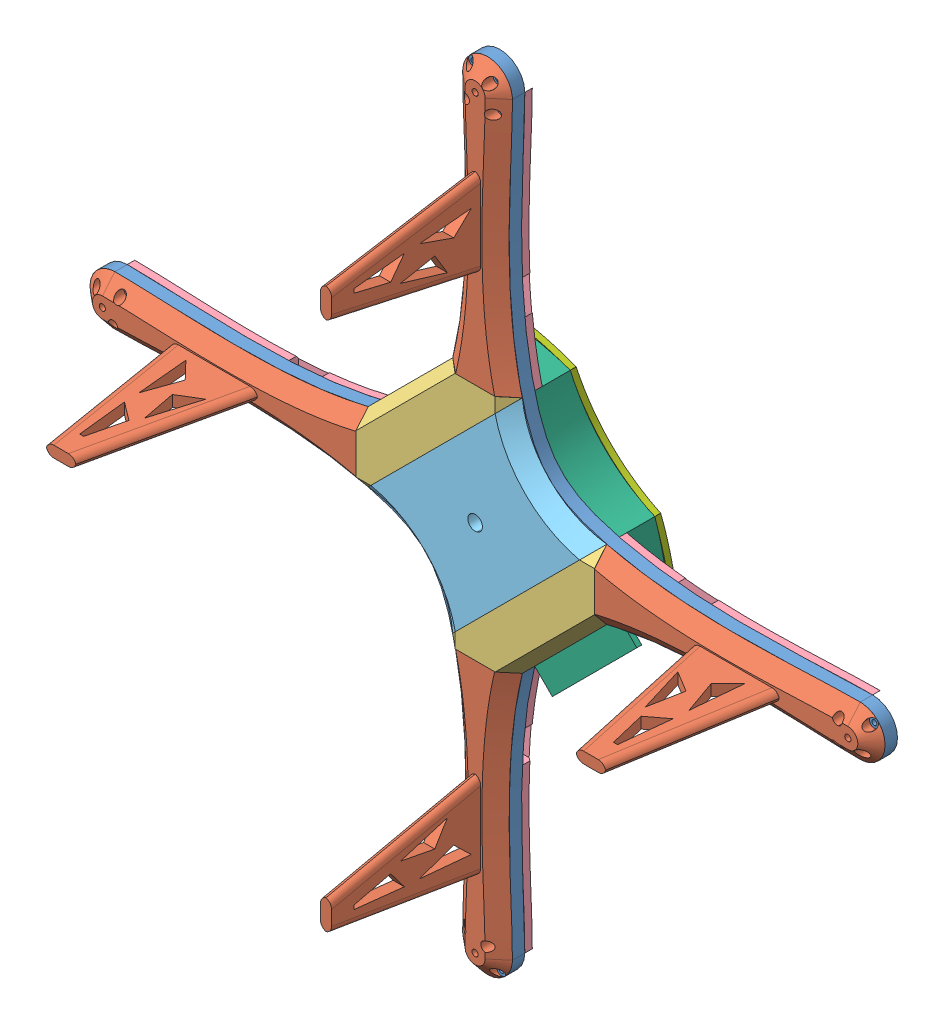
SolidWorks assembly ddddddddddddddddd, configuration Default. Lengths in mm.
Overall size (320 320 95.21).
15 component instances, 8 part files, 15 mates.
Components (placement in the parent):
- dddddddddddddd-1: dddddddddddddd [Default] at (96.5673 151.8283 268.0039) size (320 320 5)
- dddddddddddddd2-1: dddddddddddddd2 [Default] at (96.5673 151.8283 273.0039) size (112 28 65)
- dddddddddddddd2-2: dddddddddddddd2 [Default] at (96.5673 151.8283 273.0039) x (0 1 0) z (0 0 1) size (112 28 65)
- dddddddddddddd2-3: dddddddddddddd2 [Default] at (96.5673 151.8283 273.0039) x (-1 0 0) z (0 0 1) size (112 28 65)
- dddddddddddddd2-4: dddddddddddddd2 [Default] at (96.5673 151.8283 273.0039) x (0 -1 0) z (0 0 1) size (112 28 65)
- dddddddddd3-1: dddddddddd3 [Default] at (96.5673 151.8283 278.0039) x (1 0 0) z (0 0 -1) size (62 62 5)
- dddddddddd3-2: dddddddddd3 [Default] at (96.5673 151.8283 278.0039) x (-1 0 0) z (0 0 -1) size (62 62 5)
- dddddddddddd5-1: dddddddddddd5 [Default] at (96.5673 151.8283 268.0039) x (0 1 0) z (0 0 -1) size (102.01 28.01 8)
- dddddddddddd5-2: dddddddddddd5 [Default] at (96.5673 151.8283 268.0039) x (-1 0 0) z (0 0 -1) size (102.01 28.01 8)
- dddddddddddd5-3: dddddddddddd5 [Default] at (96.5673 151.8283 268.0039) x (0 -1 0) z (0 0 -1) size (102.01 28.01 8)
- dddddddddddd5-4: dddddddddddd5 [Default] at (96.5673 151.8283 268.0039) x (1 0 0) z (0 0 -1) size (102.01 28.01 8)
- ddddddddddddddd6-1: ddddddddddddddd6 [Default] at (0 0 273.0039) size (96 96 5)
- dddddddddddd7-2: dddddddddddd7 [Default] at (121.651 188.2706 266.0039) x (0 1 0) z (0 0 1) size (105.17 105.17 21.2)
- Part1^ddddddddddddddddd-1: Part1^ddddddddddddddddd [Default] at origin (virtual)
- dddddddddddddddd8-1: dddddddddddddddd8 [Default] at (121.651 188.2706 253.8113) x (0 1 0) z (0 0 1) size (100.19 100.19 13.12)
Mates (geometry in assembly coordinates):
- Coincident1: coincident: plane of dddddddddddddd-1 through (96.5673 151.8283 273.0039) normal (0 0 1); plane of dddddddddddddd2-1 through (96.5673 151.8283 273.0039) normal (0 0 -1)
- Coincident2: coincident: cylinder of dddddddddddddd-1 through (246.5673 151.8283 273.0039) axis (0 0 -1) radius 10; circle of dddddddddddddd2-1
- Coincident3: coincident: plane of dddddddddddddd2-4 through (96.5673 103.8283 278.0039) normal (0 1 0); plane of dddddddddd3-1 through (96.5673 103.8283 273.0039) normal (0 -1 0)
- Coincident4: coincident: plane of dddddddddddddd-1 through (96.5673 151.8283 273.0039) normal (0 0 1); plane of dddddddddd3-1 through (96.5673 151.8283 273.0039) normal (0 0 -1)
- Coincident5: coincident: plane of dddddddddddddd-1 through (127.5673 120.8283 273.0039) normal (0.707107 -0.707107 0); line of dddddddddd3-1 through (110.5673 103.8283 273.0039) axis (0.707107 0.707107 0)
- Coincident6: coincident: plane of dddddddddddddd-1 through (96.5673 151.8283 268.0039) normal (0 0 -1); plane of dddddddddddd5-1 through (96.5673 151.8283 268.0039) normal (0 0 1)
- Concentric2: concentric: cylinder of dddddddddddddd-1 through (96.5673 251.8283 268.0039) axis (0 0 1) radius 1; cylinder of dddddddddddd5-1 through (96.5673 251.8283 260.0039) axis (0 0 1) radius 2
- Concentric5: concentric: cylinder of dddddddddddddd-1 through (96.5673 301.8283 273.0039) axis (0 0 -1) radius 10; cylinder of dddddddddddd5-1 through (96.5673 301.8283 260.0039) axis (0 0 1) radius 10
- Coincident7: coincident: plane of dddddddddddddd-1 through (96.5673 151.8283 273.0039) normal (0 0 1); plane of ddddddddddddddd6-1 through (0 0 273.0039) normal (0 0 -1)
- Concentric6: concentric: cylinder of dddddddddddddd-1 through (96.5673 151.8283 273.0039) axis (0 0 -1) radius 2.5; cylinder of ddddddddddddddd6-1 through (96.5673 151.8283 278.0039) axis (0 0 -1) radius 2.9469
- Coincident12: coincident: plane of dddddddddddddd-1 through (96.5673 151.8283 268.0039) normal (0 0 -1); plane of dddddddddddd7-2 through (148.7774 204.0384 268.0039) normal (0 0 1)
- Concentric7: concentric: cylinder of dddddddddddddd-1 through (96.5673 151.8283 273.0039) axis (0 0 -1) radius 2.5; cylinder of dddddddddddd7-2 through (96.5673 151.8283 268.0039) axis (0 0 -1) radius 2.2992
- Coincident13: coincident: plane of dddddddddddddd-1 through (65.5673 182.8283 273.0039) normal (-0.707107 0.707107 0); plane of dddddddddddd7-2 through (48.5673 165.8283 268.0039) normal (-0.707107 0.707107 0)
- Concentric8: concentric: cylinder of dddddddddddd7-2 through (96.5673 151.8283 268.0039) axis (0 0 -1) radius 2.2992; cylinder of dddddddddddddddd8-1 through (96.5673 151.8283 241.8113) axis (0 0 1) radius 2.2992
- Coincident14: coincident: plane of dddddddddddd7-2 through (144.5673 137.8283 268.0039) normal (1 0 0); plane of dddddddddddddddd8-1 through (144.5673 137.8283 241.8113) normal (1 0 0)
